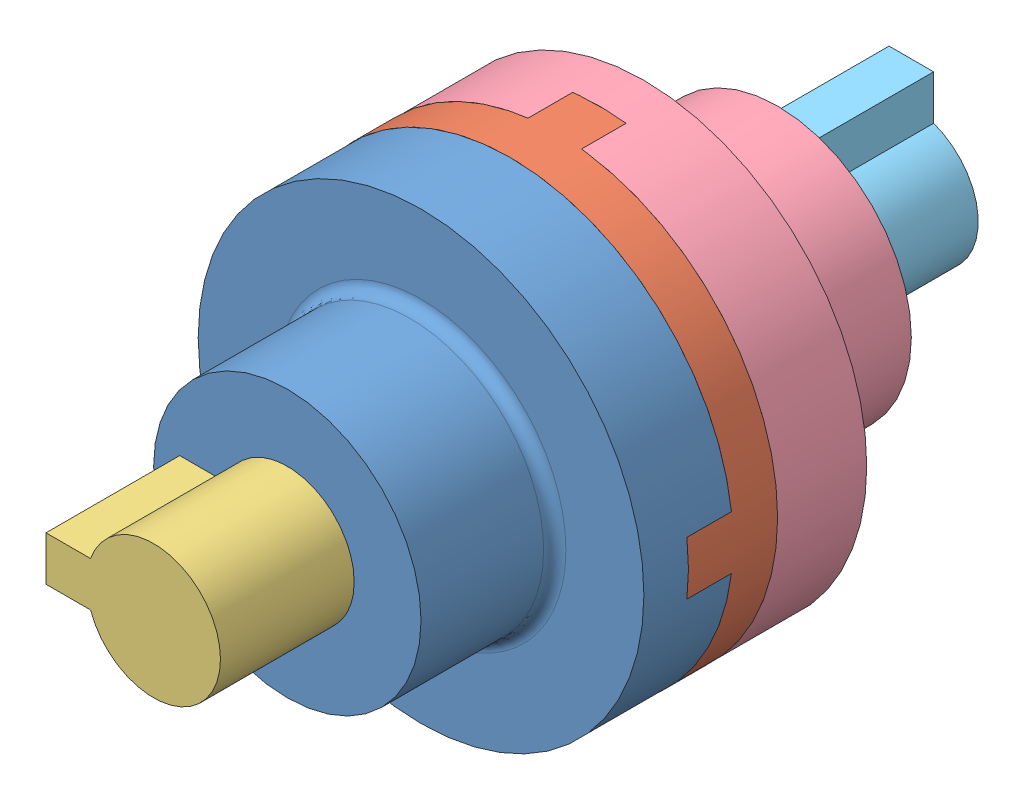
SolidWorks assembly Assem1, configuration Default. Lengths in mm.
Overall size (100 100 170).
5 component instances, 5 part files, 12 mates.
Components (placement in the parent):
- Part1-1: Part1 [Default] at (10.8753 55.9867 63.1344) size (100 100 50)
- Part2-1: Part2 [Default] at (10.8753 55.9867 63.1344) x (-1 0 0) z (0 0 -1) size (100 100 30)
- Part3-1: Part3 [Default] at (10.8753 55.9867 73.1344) size (39.14 30 70)
- Part4-1: Part4 [Default] at (10.8753 55.9867 53.1344) x (0 -1 0) z (0 0 -1) size (100 100 50)
- Part5-1: Part5 [Default] at (10.8753 55.9867 -26.8656) x (0 -1 0) z (0 0 1) size (39.14 30 70)
Mates (geometry in assembly coordinates):
- Coincident1: coincident anti-aligned: plane of Part1-1 through (10.8753 55.9867 73.1344) normal (0 0 -1); plane of Part2-1 through (10.8753 55.9867 73.1344) normal (0 0 1)
- Coincident2: coincident anti-aligned: plane of Part1-1 through (65.8753 61.9867 73.1344) normal (0 -1 0); plane of Part2-1 through (-38.7634 61.9867 73.1344) normal (0 1 0)
- Concentric1: concentric anti-aligned: cylinder of Part1-1 through (10.8753 55.9867 83.1344) axis (0 0 -1) radius 50; cylinder of Part2-1 through (10.8753 55.9867 53.1344) axis (0 0 1) radius 50
- Coincident3: coincident anti-aligned: plane of Part2-1 through (10.8753 55.9867 43.1344) normal (0 0 -1); plane of Part4-1 through (10.8753 55.9867 43.1344) normal (0 0 1)
- Coincident4: coincident anti-aligned: plane of Part2-1 through (16.8753 105.6254 43.1344) normal (1 0 0); plane of Part4-1 through (16.8753 0.9867 43.1344) normal (-1 0 0)
- Concentric2: concentric aligned: cylinder of Part2-1 through (10.8753 55.9867 53.1344) axis (0 0 1) radius 50; cylinder of Part4-1 through (10.8753 55.9867 33.1344) axis (0 0 1) radius 50
- Coincident5: coincident anti-aligned: plane of Part4-1 through (5.8753 80.1289 102.4508) normal (0 -1 0); plane of Part5-1 through (15.8753 80.1289 43.1344) normal (0 1 0)
- Concentric3: concentric aligned: cylinder of Part4-1 through (10.8753 55.9867 102.4508) axis (0 0 -1) radius 15; cylinder of Part5-1 through (10.8753 55.9867 43.1344) axis (0 0 -1) radius 15
- Coincident6: coincident: plane of Part4-1 through (10.8753 55.9867 43.1344) normal (0 0 -1); plane of Part5-1 through (10.8753 55.9867 43.1344) normal (0 0 1)
- Coincident7: coincident anti-aligned: plane of Part1-1 through (-13.2669 60.9867 13.818) normal (1 0 0); plane of Part3-1 through (-13.2669 60.9867 143.1344) normal (-1 0 0)
- Coincident8: coincident: plane of Part1-1 through (10.8753 55.9867 73.1344) normal (0 0 1); plane of Part3-1 through (10.8753 55.9867 73.1344) normal (0 0 -1)
- Concentric4: concentric anti-aligned: cylinder of Part1-1 through (10.8753 55.9867 13.818) axis (0 0 1) radius 15; cylinder of Part3-1 through (10.8753 55.9867 143.1344) axis (0 0 -1) radius 15
